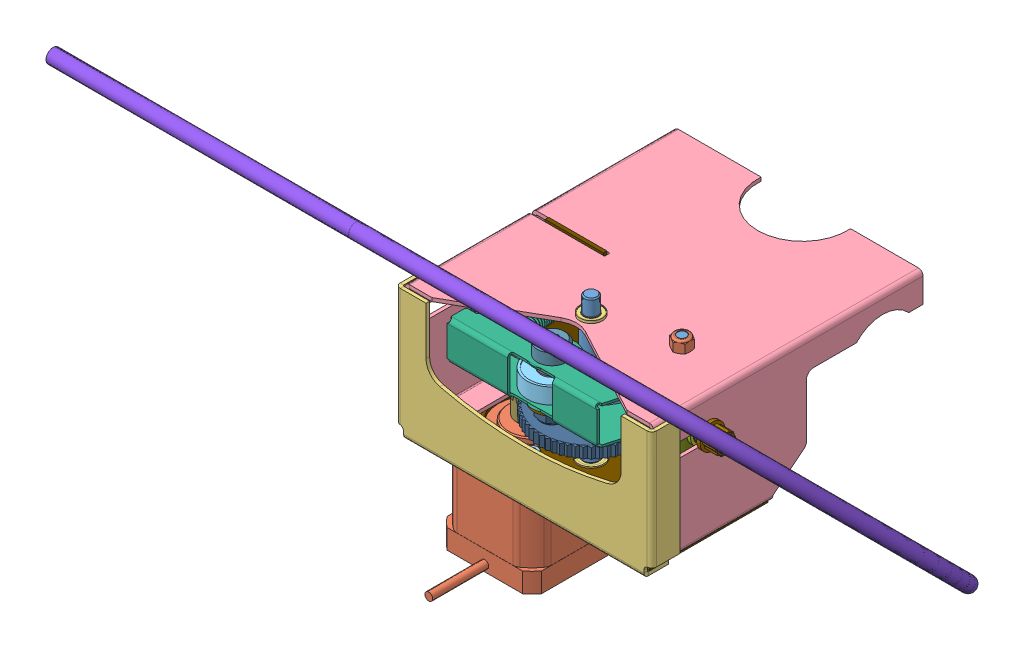
SolidWorks assembly Driver, configuration Default. Lengths in mm.
Overall size (322.35 292.26 299.17).
48 component instances, 31 part files, 71 mates.
Components (placement in the parent):
- HobbedBolt_03-1: HobbedBolt_03 [Default] at (0 0 -5) x (0 -1 0) z (-0.462364 0 0.88669) size (73 8 8)
- NEMA17_Kysan-1: NEMA17_Kysan [Default] at (-28.3309 -49.8599 -6.9804) size (42.16 70.88 67.16)
- flanged_6x10x3-1: flanged_6x10x3 [Default] at (0 13.7 -5) x (0 -1 0) z (0 0 1) size (3 11.2 11.2)
- flanged_6x10x3-2: flanged_6x10x3 [Default] at (0 -40.5 -5) x (0 1 0) z (0 0 1) size (3 11.2 11.2)
- MountPlate_1^Driver-1: MountPlate_1^Driver [Default] at origin size (111.14 55.5 120) (virtual)
- 8x22x7_ss_SB608ZZ-1: 8x22x7_ss_SB608ZZ [Default] at (0 0 12.5) x (0 1 0) z (0 0 1) size (7 22 22)
- BearingHinge^Driver-1: BearingHinge^Driver [Default] at origin size (76.5 17.01 41.28) (virtual)
- Filament^Driver-1: Filament^Driver [Default] at origin size (320.68 203 203) (virtual)
- Bowden^Driver-1: Bowden^Driver [Default] at origin size (279.6 206.35 206.35) (virtual)
- M8_ss_93475A270-1: M8_ss_93475A270 [93475A270] at (0 -9.9 12.5) x (0.986555 0 0.163428) z (0 -1 0) size (16 16 1.4)
- Nyloc_M6_93625A250-1: Nyloc_M6_93625A250 [93625A250] at (0 -9.9 12.5) x (-0.837169 0 -0.546944) z (-0.546944 0 0.837169) size (10 6.19 11.55)
- SAIPOZ5_20-1: SAIPOZ5_20 [Default] at (-33 8 -25.5) x (0 0 -1) z (-1 0 0) size (20 9.2 8)
  - SAIPOZ5_20b-1: SAIPOZ5_20b [Milled] at origin size (20 4.2 5)
  - KNTR5-1: KNTR5 [Default] at (7.6 0 0) x (-1 0 0) z (0 0 1) size (3.2 9.2 8)
- SAIPOZ5_20-2: SAIPOZ5_20 [Default] at (-33 -8 -25.5) x (0 0 -1) z (1 0 0) size (20 9.2 8)
  - SAIPOZ5_20b-1: SAIPOZ5_20b [Milled] at origin size (20 4.2 5)
  - KNTR5-1: KNTR5 [Default] at (7.6 0 0) x (-1 0 0) z (0 0 1) size (3.2 9.2 8)
- Spacer_8-2x10x4_SMKB8-4-1: Spacer_8-2x10x4_SMKB8-4 [Default] at (0 5.5 12.5) size (10 4 10)
- Spacer_8-2x10x4_SMKB8-4-2: Spacer_8-2x10x4_SMKB8-4 [Default] at (0 -5.5 12.5) size (10 4 10)
- Shoulder_M8x15_SMSB8-15-1: Shoulder_M8x15_SMSB8-15 [Default] at (0 8.5 12.5) x (0 -1 0) z (-0.063505 0 0.997982) size (30 13 13)
- Spacer_6x12x9-5_CLJGJ12-6-9-5-1: Spacer_6x12x9-5_CLJGJ12-6-9-5 [Default] at (33 0 -12.5) x (0 1 0) z (-0.087208 0 0.99619) size (8.5 12 12)
- Spacer_6x12x9-5_CLJGJ12-6-9-5-2: Spacer_6x12x9-5_CLJGJ12-6-9-5 [Default] at (33 0 -12.5) x (0 -1 0) z (0 0 1) size (8.5 12 12)
- Spacer_6x14x32_CLJJ6-14-32-1: Spacer_6x14x32_CLJJ6-14-32 [Default] at (33 -24.5 -12.5) x (0 -1 0) z (0.157604 0 0.987502) size (32 14 14)
- Spacer_6x10x2_WSJJ10-6-2-1: Spacer_6x10x2_WSJJ10-6-2 [Default] at (33 11 -12.5) x (0 1 0) z (-0.566596 0 0.823996) size (5 10 10)
- MountPlate_2^Driver-2: MountPlate_2^Driver [Default] at origin size (110.06 58.09 56.07) (virtual)
- Shoulder_M6x55_MSB6-55-2: Shoulder_M6x55_MSB6-55 [Default] at (33 -42.0875 -12.5) x (0 1 0) z (-1 0 0) size (66 9 9)
- Nyloc_M4_93625A150-1: Nyloc_M4_93625A150 [93625A150] at (33 15 -12.5) size (7 5.12 8.08)
- MountPlate_3^Driver-2: MountPlate_3^Driver [Default] at origin size (114.32 57.78 12.56) (virtual)
- M3_93475A210-1: M3_93475A210 [93475A210] at (-43.8309 -40.5 8.5196) x (1 0 0) z (0 -1 0) size (7 7 0.45)
- M3_93475A210-2: M3_93475A210 [93475A210] at (-12.8309 -40.5 8.5196) x (1 0 0) z (0 -1 0) size (7 7 0.45)
- M3_93475A210-3: M3_93475A210 [93475A210] at (-43.8309 -40.5 -22.4804) x (1 0 0) z (0 -1 0) size (7 7 0.45)
- M3_93475A210-4: M3_93475A210 [93475A210] at (-12.8309 -40.5 -22.4804) x (1 0 0) z (0 -1 0) size (7 7 0.45)
- M3x4_91292A109-1: M3x4_91292A109 [91292A109] at (-12.8309 -44.05 8.5196) x (1 0 0) z (0 -1 0) size (5.5 5.5 7.14)
- M3x4_91292A109-2: M3x4_91292A109 [91292A109] at (-43.8309 -44.05 8.5196) x (1 0 0) z (0 -1 0) size (5.5 5.5 7.14)
- M3x4_91292A109-3: M3x4_91292A109 [91292A109] at (-43.8309 -44.05 -22.4804) x (1 0 0) z (0 -1 0) size (5.5 5.5 7.14)
- M3x4_91292A109-4: M3x4_91292A109 [91292A109] at (-12.8309 -44.05 -22.4804) x (1 0 0) z (0 -1 0) size (5.5 5.5 7.14)
- Tension_6x30x0-7_BUU6-30-1: Tension_6x30x0-7_BUU6-30 [Default] at (-33.4598 -8.696 -21.0222) x (-0.301998 0.952646 0.035526) z (0.952175 0.303246 -0.03747) size (6 40 6)
- Tension_6x30x0-7_BUU6-30-2: Tension_6x30x0-7_BUU6-30 [Default] at (-33.2355 8.0086 6.1423) x (0.17584 0.984225 0.019517) z (-0.984134 0.175277 0.027532) size (6 40 6)
- 1-4x28_flange_90759A150-1: 1-4x28_flange_90759A150 [90759A150] at (47.3845 0 0) x (0 0 1) z (-1 0 0) size (11.11 11.11 7.8)
- 1-4_PTFE_95630A217-1: 1-4_PTFE_95630A217 [95630A217] at (54.9251 0 0) x (0 0 1) z (-1 0 0) size (8.64 8.64 0.56)
- 1-4_PTFE_95630A217-2: 1-4_PTFE_95630A217 [95630A217] at (57.0714 0 0) x (0 0 1) z (-1 0 0) size (8.64 8.64 0.56)
- 1-4x20_flange_90759A100-1: 1-4x20_flange_90759A100 [90759A100] at (65.1708 0 0) x (0 -0.383049 -0.923728) z (1 0 0) size (11.11 11.11 8.07)
- GEABP0_8_56_5_B_8-1: GEABP0_8_56_5_B_8 [Default] at (0 -19.9 -5) x (0.993989 0 0.10948) z (0 1 0) size (46.4 46.4 14)
  - GEABP0_8_56_5_B_8_b-1: GEABP0_8_56_5_B_8_b [Default] x (-1 0 0) z (0 0 -1) size (46.4 46.4 14)
  - Hexagon_socket_set_screw_with_flat_point_DIN_913___M4x3-1: Hexagon_socket_set_screw_with_flat_point_DIN_913___M4x3 [Default] at (0 7 -10) x (0 -1 0) z (1 0 0) size (3.1 4 4)
- GEABS0_8_15_7_K_5-1: GEABS0_8_15_7_K_5 [Default] at (-28.3309 -18.9 -6.9804) x (0 -1 0) z (-0.0416 0 0.999134) size (20 13.68 13.6)
  - GEABS0_8_15_7_5_1-1: GEABS0_8_15_7_5_1 [Default] x (0 0 -1) z (1 0 0) size (13.6 13.6 20)
  - Hexagon_socket_set_screw_with_flat_point_DIN_913___M3x4-1: Hexagon_socket_set_screw_with_flat_point_DIN_913___M3x4 [Default] at (17 6.8 0) x (0 -1 0) z (0 0 1) size (4.08 3 3)
Mates (geometry in assembly coordinates):
- Concentric1: concentric aligned: cylinder of HobbedBolt_03-1 through (0 0 -5) axis (0 1 0) radius 4; circle of assembly
- Coincident2: coincident anti-aligned: plane of HobbedBolt_03-1; plane of assembly through (0 0 0) normal (0 1 0)
- Parallel1: parallel: plane of NEMA17_Kysan-1 through (-15.8518 -80.2999 -27.9989) normal (0 0 -1); line of assembly
- Coincident5: coincident anti-aligned: plane of HobbedBolt_03-1 through (2.6601 13.1 -3.6129) normal (0 1 0); plane of flanged_6x10x3-1 through (5.6 13.1 -5) normal (0 -1 0)
- Concentric7: concentric aligned: cylinder of HobbedBolt_03-1 through (0 0 -5) axis (0 1 0) radius 3; cylinder of flanged_6x10x3-1 through (0 23.3318 -5) axis (0 1 0) radius 3
- Coincident6: coincident anti-aligned: plane of HobbedBolt_03-1 through (3.5468 -39.9 -3.1505) normal (0 -1 0); plane of flanged_6x10x3-2 through (-5.6 -39.9 -5) normal (0 1 0)
- Concentric8: concentric anti-aligned: cylinder of HobbedBolt_03-1 through (0 0 -5) axis (0 1 0) radius 3; cylinder of flanged_6x10x3-2 through (0 -50.1318 -5) axis (0 -1 0) radius 3
- Coincident7: coincident anti-aligned: cylinder of 8x22x7_ss_SB608ZZ-1 through (0 -3.3544 12.5) axis (0 -1 0) radius 11; circle of assembly
- Coincident8: coincident aligned: plane of 8x22x7_ss_SB608ZZ-1; plane of assembly through (0 0 0) normal (0 1 0)
- Coincident12: coincident anti-aligned: plane of BearingHinge^Driver-1 through (-33 -8.5 12.5) normal (0 -1 0); plane of M8_ss_93475A270-1 through (0 -8.5 12.5) normal (0 1 0)
- Concentric12: concentric aligned: cylinder of 8x22x7_ss_SB608ZZ-1 through (0 -3.3544 12.5) axis (0 -1 0) radius 11; cylinder of M8_ss_93475A270-1 through (0 -8.5 12.5) axis (0 -1 0) radius 8
- Coincident14: coincident anti-aligned: plane of M8_ss_93475A270-1 through (0 -9.9 12.5) normal (0 -1 0); plane of Nyloc_M6_93625A250-1 through (8.9225 -9.9 7.9846) normal (0 1 0)
- Concentric14: concentric anti-aligned: cylinder of M8_ss_93475A270-1 through (0 -8.5 12.5) axis (0 -1 0) radius 8; cylinder of Nyloc_M6_93625A250-1 through (0 -14.9762 12.5) axis (0 1 0) radius 2.538
- Parallel2: parallel anti-aligned: cylinder of SAIPOZ5_20-2/SAIPOZ5_20b-1 through (-33 -8 -45.5) axis (0 0 1) radius 2.5; line of assembly
- Parallel3: parallel anti-aligned: cylinder of SAIPOZ5_20-1/SAIPOZ5_20b-1 through (-33 8 -45.5) axis (0 0 1) radius 2.5; line of assembly
- Concentric19: concentric: cylinder of SAIPOZ5_20-1/SAIPOZ5_20b-1 through (-33 9.5 -27.5) axis (0 -1 0) radius 1; point of assembly
- Concentric20: concentric: cylinder of SAIPOZ5_20-2/SAIPOZ5_20b-1 through (-33 -9.5 -27.5) axis (0 1 0) radius 1; point of assembly
- Coincident25: coincident anti-aligned: plane of SAIPOZ5_20-2/SAIPOZ5_20b-1; plane of assembly through (0 -8 0) normal (0 -1 0)
- Coincident26: coincident aligned: plane of SAIPOZ5_20-1/SAIPOZ5_20b-1; plane of assembly through (0 8 0) normal (0 -1 0)
- Coincident27: coincident anti-aligned: plane of BearingHinge^Driver-1 through (-33 7.5 12.5) normal (0 -1 0); plane of Spacer_8-2x10x4_SMKB8-4-1 through (4.1 7.5 12.5) normal (0 1 0)
- Coincident28: coincident anti-aligned: plane of BearingHinge^Driver-1 through (-33 -7.5 12.5) normal (0 1 0); plane of Spacer_8-2x10x4_SMKB8-4-2 through (4.1 -7.5 12.5) normal (0 -1 0)
- Concentric21: concentric anti-aligned: cylinder of 8x22x7_ss_SB608ZZ-1 through (0 -3.3544 12.5) axis (0 -1 0) radius 11; cylinder of Spacer_8-2x10x4_SMKB8-4-2 through (0 7.5095 12.5) axis (0 1 0) radius 5
- Concentric22: concentric anti-aligned: cylinder of 8x22x7_ss_SB608ZZ-1 through (0 -3.3544 12.5) axis (0 -1 0) radius 11; cylinder of Spacer_8-2x10x4_SMKB8-4-1 through (0 18.5095 12.5) axis (0 1 0) radius 5
- Concentric23: concentric anti-aligned: cylinder of 8x22x7_ss_SB608ZZ-1 through (0 -3.3544 12.5) axis (0 -1 0) radius 11; cylinder of Shoulder_M8x15_SMSB8-15-1 through (0 34.5126 12.5) axis (0 1 0) radius 4
- Coincident29: coincident anti-aligned: plane of BearingHinge^Driver-1 through (-33 8.5 12.5) normal (0 1 0); plane of Shoulder_M8x15_SMSB8-15-1 through (6.4869 8.5 12.9128) normal (0 -1 0)
- Coincident30: coincident anti-aligned: plane of BearingHinge^Driver-1 through (-33 7.5 12.5) normal (0 -1 0); plane of Spacer_6x12x9-5_CLJGJ12-6-9-5-1 through (28.5171 7.5 -12.8924) normal (0 1 0)
- Coincident31: coincident anti-aligned: plane of BearingHinge^Driver-1 through (-33 -7.5 12.5) normal (0 1 0); plane of Spacer_6x12x9-5_CLJGJ12-6-9-5-2 through (37.5 -7.5 -12.5) normal (0 -1 0)
- Concentric24: concentric aligned: cylinder of BearingHinge^Driver-1 through (33 -8.5 -12.5) axis (0 1 0) radius 4.5; cylinder of Spacer_6x12x9-5_CLJGJ12-6-9-5-2 through (33 0 -12.5) axis (0 1 0) radius 6
- Concentric25: concentric aligned: cylinder of BearingHinge^Driver-1 through (33 8.5 -12.5) axis (0 -1 0) radius 4.5; cylinder of Spacer_6x12x9-5_CLJGJ12-6-9-5-1 through (33 0 -12.5) axis (0 -1 0) radius 6
- Concentric26: concentric anti-aligned: cylinder of Spacer_6x12x9-5_CLJGJ12-6-9-5-1 through (33 0 -12.5) axis (0 -1 0) radius 6; cylinder of Spacer_6x14x32_CLJJ6-14-32-1 through (33 12.5032 -12.5) axis (0 1 0) radius 7
- Concentric27: concentric anti-aligned: cylinder of Spacer_6x12x9-5_CLJGJ12-6-9-5-2 through (33 0 -12.5) axis (0 1 0) radius 6; cylinder of Spacer_6x10x2_WSJJ10-6-2-1 through (33 -26.0032 -12.5) axis (0 -1 0) radius 5
- Concentric31: concentric anti-aligned: cylinder of Spacer_6x14x32_CLJJ6-14-32-1 through (33 12.5032 -12.5) axis (0 1 0) radius 7; cylinder of Shoulder_M6x55_MSB6-55-2 through (33 -57.5357 -12.5) axis (0 -1 0) radius 3
- Coincident39: coincident anti-aligned: plane of NEMA17_Kysan-1 through (-28.3309 -42.0875 -6.9804) normal (0 1 0); plane of MountPlate_2^Driver-2 through (-48 -42.0875 -31) normal (0 -1 0)
- Coincident40: coincident anti-aligned: plane of BearingHinge^Driver-1 through (-33 8.5 12.5) normal (0 1 0); plane of Spacer_6x10x2_WSJJ10-6-2-1 through (28.88 8.5 -15.333) normal (0 -1 0)
- Coincident41: coincident anti-aligned: plane of BearingHinge^Driver-1 through (-33 -8.5 12.5) normal (0 -1 0); plane of Spacer_6x14x32_CLJJ6-14-32-1 through (39.9125 -8.5 -13.6032) normal (0 1 0)
- Coincident42: coincident aligned: plane of M3_93475A210-3 through (-43.8309 -40.05 -22.4804) normal (0 1 0); plane of M3_93475A210-1 through (-43.8309 -40.05 8.5196) normal (0 1 0)
- Coincident43: coincident aligned: plane of M3_93475A210-3 through (-43.8309 -40.05 -22.4804) normal (0 1 0); plane of M3_93475A210-4 through (-12.8309 -40.05 -22.4804) normal (0 1 0)
- Coincident44: coincident aligned: plane of M3_93475A210-3 through (-43.8309 -40.05 -22.4804) normal (0 1 0); plane of M3_93475A210-2 through (-12.8309 -40.05 8.5196) normal (0 1 0)
- Coincident45: coincident anti-aligned: plane of MountPlate_2^Driver-2 through (-48 -40.5 -31) normal (0 1 0); plane of M3_93475A210-1 through (-43.8309 -40.5 8.5196) normal (0 -1 0)
- Concentric33: concentric aligned: cylinder of MountPlate_2^Driver-2 through (-43.8309 16.001 8.5196) axis (0 -1 0) radius 1.75; cylinder of M3_93475A210-1 through (-43.8309 -40.05 8.5196) axis (0 -1 0) radius 3.5
- Concentric34: concentric aligned: cylinder of MountPlate_2^Driver-2 through (-12.8309 16.001 8.5196) axis (0 -1 0) radius 1.75; cylinder of M3_93475A210-2 through (-12.8309 -40.05 8.5196) axis (0 -1 0) radius 3.5
- Concentric35: concentric aligned: cylinder of MountPlate_2^Driver-2 through (-43.8309 16.001 -22.4804) axis (0 -1 0) radius 1.75; cylinder of M3_93475A210-3 through (-43.8309 -40.05 -22.4804) axis (0 -1 0) radius 3.5
- Concentric36: concentric aligned: cylinder of MountPlate_2^Driver-2 through (-12.8309 16.001 -22.4804) axis (0 -1 0) radius 1.75; cylinder of M3_93475A210-4 through (-12.8309 -40.05 -22.4804) axis (0 -1 0) radius 3.5
- Coincident46: coincident aligned: plane of M3x4_91292A109-1 through (-12.8309 -40.05 8.5196) normal (0 -1 0); plane of M3x4_91292A109-2 through (-43.8309 -40.05 8.5196) normal (0 -1 0)
- Coincident47: coincident aligned: plane of M3x4_91292A109-1 through (-12.8309 -40.05 8.5196) normal (0 -1 0); plane of M3x4_91292A109-3 through (-43.8309 -40.05 -22.4804) normal (0 -1 0)
- Coincident48: coincident aligned: plane of M3x4_91292A109-1 through (-12.8309 -40.05 8.5196) normal (0 -1 0); plane of M3x4_91292A109-4 through (-12.8309 -40.05 -22.4804) normal (0 -1 0)
- Coincident49: coincident anti-aligned: plane of M3_93475A210-4 through (-12.8309 -40.05 -22.4804) normal (0 1 0); plane of M3x4_91292A109-4 through (-12.8309 -40.05 -22.4804) normal (0 -1 0)
- Concentric37: concentric aligned: cylinder of MountPlate_2^Driver-2 through (-12.8309 16.001 -22.4804) axis (0 -1 0) radius 1.75; cylinder of M3x4_91292A109-4 through (-12.8309 -37.05 -22.4804) axis (0 -1 0) radius 2.75
- Concentric38: concentric aligned: cylinder of MountPlate_2^Driver-2 through (-43.8309 16.001 -22.4804) axis (0 -1 0) radius 1.75; cylinder of M3x4_91292A109-3 through (-43.8309 -37.05 -22.4804) axis (0 -1 0) radius 2.75
- Concentric39: concentric aligned: cylinder of MountPlate_2^Driver-2 through (-43.8309 16.001 8.5196) axis (0 -1 0) radius 1.75; cylinder of M3x4_91292A109-2 through (-43.8309 -37.05 8.5196) axis (0 -1 0) radius 2.75
- Concentric40: concentric aligned: cylinder of MountPlate_2^Driver-2 through (-12.8309 16.001 8.5196) axis (0 -1 0) radius 1.75; cylinder of M3x4_91292A109-1 through (-12.8309 -37.05 8.5196) axis (0 -1 0) radius 2.75
- Concentric41: concentric anti-aligned: cylinder of 1-4x28_flange_90759A150-1 through (53.3376 0 0) axis (1 0 0) radius 5.5563; cylinder of 1-4_PTFE_95630A217-1 through (55.4839 0 0) axis (-1 0 0) radius 4.318
- Concentric42: concentric anti-aligned: cylinder of 1-4x28_flange_90759A150-1 through (53.3376 0 0) axis (1 0 0) radius 5.5563; cylinder of 1-4_PTFE_95630A217-2 through (57.6302 0 0) axis (-1 0 0) radius 4.318
- Concentric43: concentric anti-aligned: cylinder of 1-4x28_flange_90759A150-1 through (53.3376 0 0) axis (1 0 0) radius 5.5563; cylinder of 1-4x20_flange_90759A100-1 through (59.2177 0 0) axis (-1 0 0) radius 5.5563
- Coincident50: coincident anti-aligned: plane of 1-4_PTFE_95630A217-2 through (57.6302 0 0) normal (1 0 0); plane of 1-4x20_flange_90759A100-1 through (57.6302 7.87 1.0329) normal (-1 0 0)
- Coincident51: coincident anti-aligned: plane of 1-4x28_flange_90759A150-1 through (54.9251 6.8741 -3.9688) normal (1 0 0); plane of 1-4_PTFE_95630A217-1 through (54.9251 0 0) normal (-1 0 0)
- Coincident52: coincident anti-aligned: plane of MountPlate_1^Driver-1 through (55.4839 137.9286 24) normal (-1 0 0); plane of 1-4_PTFE_95630A217-1 through (55.4839 0 0) normal (1 0 0)
- Coincident53: coincident anti-aligned: plane of MountPlate_1^Driver-1 through (57.0714 137.9286 24) normal (1 0 0); plane of 1-4_PTFE_95630A217-2 through (57.0714 0 0) normal (-1 0 0)
- Concentric44: concentric aligned: cylinder of Filament^Driver-1 through (100 0 0) axis (-1 0 0) radius 1.5; cylinder of 1-4x20_flange_90759A100-1 through (59.2177 0 0) axis (-1 0 0) radius 5.5563
- Concentric45: concentric aligned: cylinder of NEMA17_Kysan-1 through (-28.3309 -49.8599 -6.9804) axis (0 -1 0) radius 2.5; cylinder of GEABS0_8_15_7_K_5-1/GEABS0_8_15_7_5_1-1 through (-28.3309 -18.9 -6.9804) axis (0 -1 0) radius 2.5
- Concentric46: concentric anti-aligned: cylinder of GEABS0_8_15_7_K_5-1/GEABS0_8_15_7_5_1-1 through (-28.3309 -18.9 -6.9804) axis (0 -1 0) radius 6.8; circle of assembly
- Concentric47: concentric anti-aligned: cylinder of HobbedBolt_03-1 through (0 0 -5) axis (0 1 0) radius 4; cylinder of GEABP0_8_56_5_B_8-1/GEABP0_8_56_5_B_8_b-1 through (0 -19.9 -5) axis (0 -1 0) radius 7
- Distance2: distance = 1 mm aligned: plane of GEABP0_8_56_5_B_8-1/GEABP0_8_56_5_B_8_b-1 through (0.4708 -19.9 -9.2742) normal (0 1 0); plane of GEABS0_8_15_7_K_5-1/GEABS0_8_15_7_5_1-1 through (-25.5333 -18.9 -6.8639) normal (0 1 0)
- Distance1: distance = 4 mm anti-aligned: plane of GEABP0_8_56_5_B_8-1/GEABP0_8_56_5_B_8_b-1 through (0.4708 -19.9 -9.2742) normal (0 1 0); plane of Nyloc_M6_93625A250-1 through (8.9225 -15.9 7.9846) normal (0 -1 0)
- Coincident56: coincident anti-aligned: plane of MountPlate_2^Driver-2 through (-48 -42.0875 -31) normal (0 -1 0); plane of Shoulder_M6x55_MSB6-55-2 through (33 -42.0875 -17) normal (0 1 0)
- Coincident57: coincident anti-aligned: plane of ? through (-68 15 24) normal (0 1 0); plane of Nyloc_M4_93625A150-1 through (40 15 -12.5) normal (0 -1 0)
- PLANE2: unknown: plane of ? through (-33 7.5 12.5) normal (0 -1 0); plane of ? through (-33 8.5 12.5) normal (0 1 0)
- PLANE3: unknown: plane of ? through (-33 -8.5 12.5) normal (0 -1 0); plane of ? through (-33 -7.5 12.5) normal (0 1 0)
- Sketch2: unknown = 42.2447 mm: axis of ? through (-33 8.5 12.5) axis (0 -1 0)
- Sketch3: unknown: unknown of ?; unknown of flanged_6x10x3-2; unknown of NEMA17_Kysan-1; unknown of NEMA17_Kysan-1; unknown of ?; unknown of ?; unknown of flanged_6x10x3-2; unknown of Spacer_6x10x2_WSJJ10-6-2-1; unknown of ?; unknown of ?
- PLANE4: unknown: plane of ? through (56 13.4125 24) normal (0 0 1); unknown of ?; unknown of ?; unknown of ?; unknown of ?; unknown of ?; unknown of ?; unknown of ?; unknown of ?; unknown of ?; unknown of ?; unknown of ?; unknown of SAIPOZ5_20-1/SAIPOZ5_20b-1; unknown of SAIPOZ5_20-2/SAIPOZ5_20b-1; unknown of SAIPOZ5_20-2/SAIPOZ5_20b-1; unknown of SAIPOZ5_20-1/SAIPOZ5_20b-1; unknown of SAIPOZ5_20-2/KNTR5-1; unknown of SAIPOZ5_20-1/SAIPOZ5_20b-1; unknown of SAIPOZ5_20-2/SAIPOZ5_20b-1; unknown of SAIPOZ5_20-2/SAIPOZ5_20b-1; unknown of SAIPOZ5_20-1/SAIPOZ5_20b-1; unknown of SAIPOZ5_20-2/KNTR5-1; unknown of ?; unknown of ?; unknown of ?; unknown of ?; unknown of ?; unknown of ?; unknown of ?; unknown of ?; unknown of ?; unknown of ?; unknown of ?; unknown of ?; unknown of 8x22x7_ss_SB608ZZ-1; unknown of ?; unknown of ?; unknown of 8x22x7_ss_SB608ZZ-1; unknown of NEMA17_Kysan-1; unknown of NEMA17_Kysan-1; unknown of NEMA17_Kysan-1; unknown of NEMA17_Kysan-1; unknown of NEMA17_Kysan-1; unknown of NEMA17_Kysan-1; unknown of NEMA17_Kysan-1; unknown of NEMA17_Kysan-1; unknown of NEMA17_Kysan-1; unknown of NEMA17_Kysan-1; unknown of M3_93475A210-1; unknown of NEMA17_Kysan-1; unknown of ?; unknown of M3x4_91292A109-3; unknown of M3_93475A210-1; unknown of NEMA17_Kysan-1; unknown of ?; unknown of M3x4_91292A109-3; unknown of 1-4x28_flange_90759A150-1; unknown of 1-4x28_flange_90759A150-1; unknown of ?; unknown of ?; unknown of ?; unknown of ?; unknown of ?; unknown of 1-4x28_flange_90759A150-1
